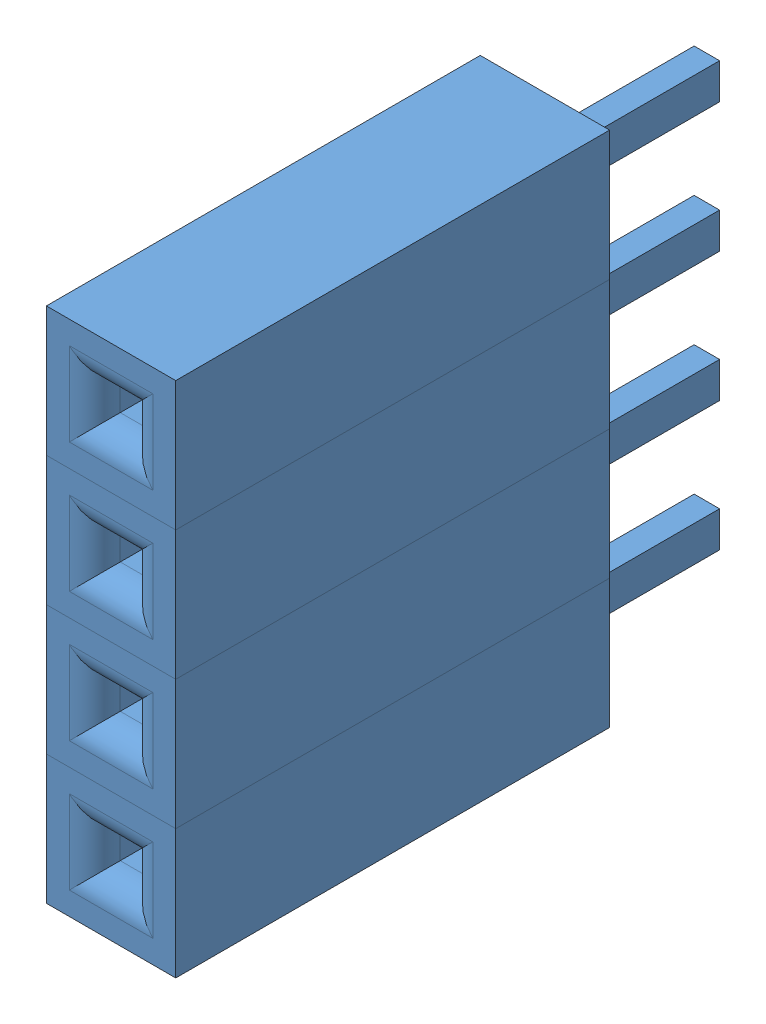
SolidWorks assembly Female Header 4 Pin, configuration Default. Lengths in mm.
Overall size (2.54 10.16 11.8).
4 component instances, 1 part files, 0 mates.
Components (placement in the parent):
- Female Header Pin-1: Female Header Pin [Default] at (-68.9815 11.3833 25.997) size (2.54 2.54 11.8)
- Female Header Pin-2: Female Header Pin [Default] at (-68.9815 13.9233 25.997) size (2.54 2.54 11.8)
- Female Header Pin-3: Female Header Pin [Default] at (-68.9815 16.4633 25.997) size (2.54 2.54 11.8)
- Female Header Pin-4: Female Header Pin [Default] at (-68.9815 19.0033 25.997) size (2.54 2.54 11.8)
